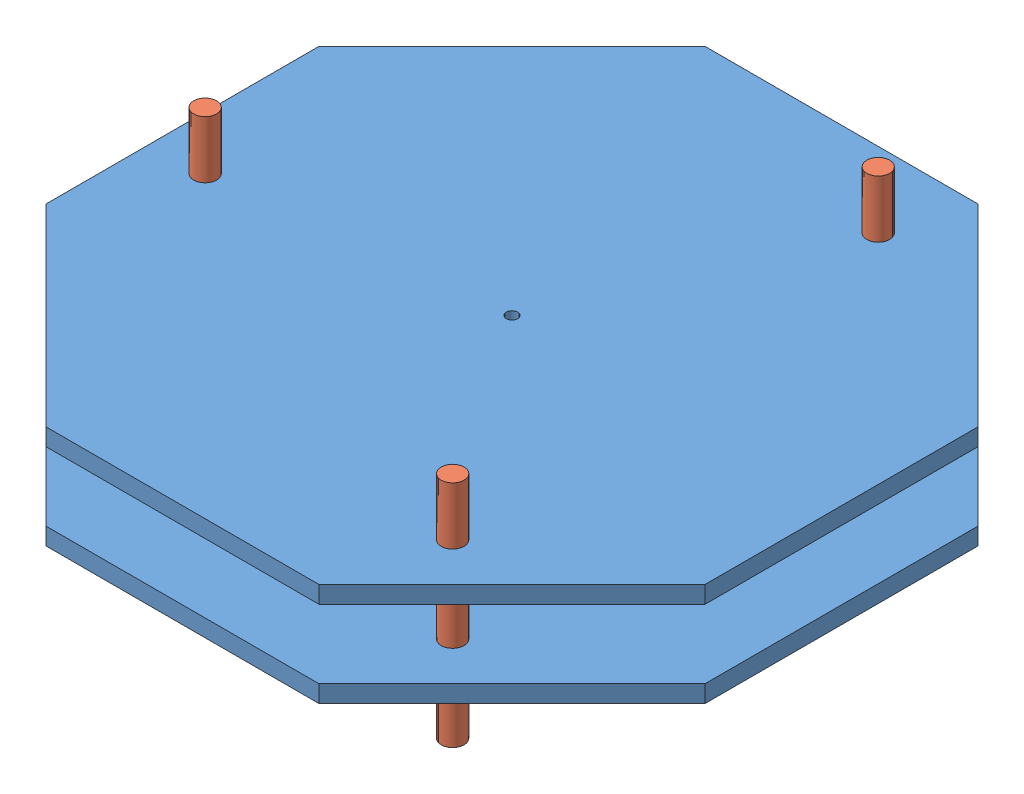
SolidWorks assembly carte avec support, configuration Défaut. Lengths in mm.
Overall size (115 40 115).
5 component instances, 2 part files, 10 mates.
Components (placement in the parent):
- carte-1: carte [Défaut] at (-3.5379 2.2909 0) size (115 3 115)
- axe carte-1: axe carte [Défaut] at (35.8948 -24.7091 42.8197) x (1 0 0) z (0 1 0) size (4 4 40)
- axe carte-2: axe carte [Défaut] at (26.6571 -24.7091 -40.6877) x (1 0 0) z (0 1 0) size (4 4 40)
- axe carte-3: axe carte [Défaut] at (-41.0435 -24.7091 9.0661) x (1 0 0) z (0 1 0) size (4 4 40)
- carte-2: carte [Défaut] at (-3.5379 -12.7091 0) size (115 3 115)
Mates (geometry in assembly coordinates):
- Coaxiale1: concentric anti-aligned: cylinder of carte-1 through (25.1875 2.2909 39.087) axis (0 1 0) radius 2; cylinder of axe carte-1 through (25.1875 15.2909 39.087) axis (0 -1 0) radius 2
- Distance1: distance = 10 mm aligned: plane of axe carte-1 through (25.1875 15.2909 39.087) normal (0 1 0); plane of carte-1 through (-3.5379 5.2909 -81.3173) normal (0 1 0)
- Coaxiale2: concentric anti-aligned: cylinder of carte-1 through (15.9498 2.2909 -44.4204) axis (0 1 0) radius 2; cylinder of axe carte-2 through (15.9498 15.2909 -44.4204) axis (0 -1 0) radius 2
- Distance2: distance = 10 mm aligned: plane of axe carte-2 through (15.9498 15.2909 -44.4204) normal (0 1 0); plane of carte-1 through (-3.5379 5.2909 -81.3173) normal (0 1 0)
- Coaxiale3: concentric anti-aligned: cylinder of carte-1 through (-51.7509 2.2909 5.3334) axis (0 1 0) radius 2; cylinder of axe carte-3 through (-51.7509 15.2909 5.3334) axis (0 -1 0) radius 2
- Distance3: distance = 10 mm aligned: plane of axe carte-3 through (-51.7509 15.2909 5.3334) normal (0 1 0); plane of carte-1 through (-3.5379 5.2909 -81.3173) normal (0 1 0)
- Parallèle2: parallel anti-aligned: cylinder of axe carte-1 through (25.1875 15.2909 39.087) axis (0 -1 0) radius 2; cylinder of carte-2 through (25.1875 -12.7091 39.087) axis (0 1 0) radius 2
- Distance5: distance = 15 mm aligned: plane of carte-1 through (-3.5379 5.2909 -81.3173) normal (0 1 0); plane of carte-2 through (-3.5379 -9.7091 -81.3173) normal (0 1 0)
- Coïncidente2: coincident anti-aligned: cylinder of axe carte-1 through (25.1875 15.2909 39.087) axis (0 -1 0) radius 2; circle of carte-2
- Parallèle3: parallel aligned: plane of carte-1 through (-27.3552 5.2909 57.5) normal (0 0 1); plane of carte-2 through (-27.3552 -9.7091 57.5) normal (0 0 1)
